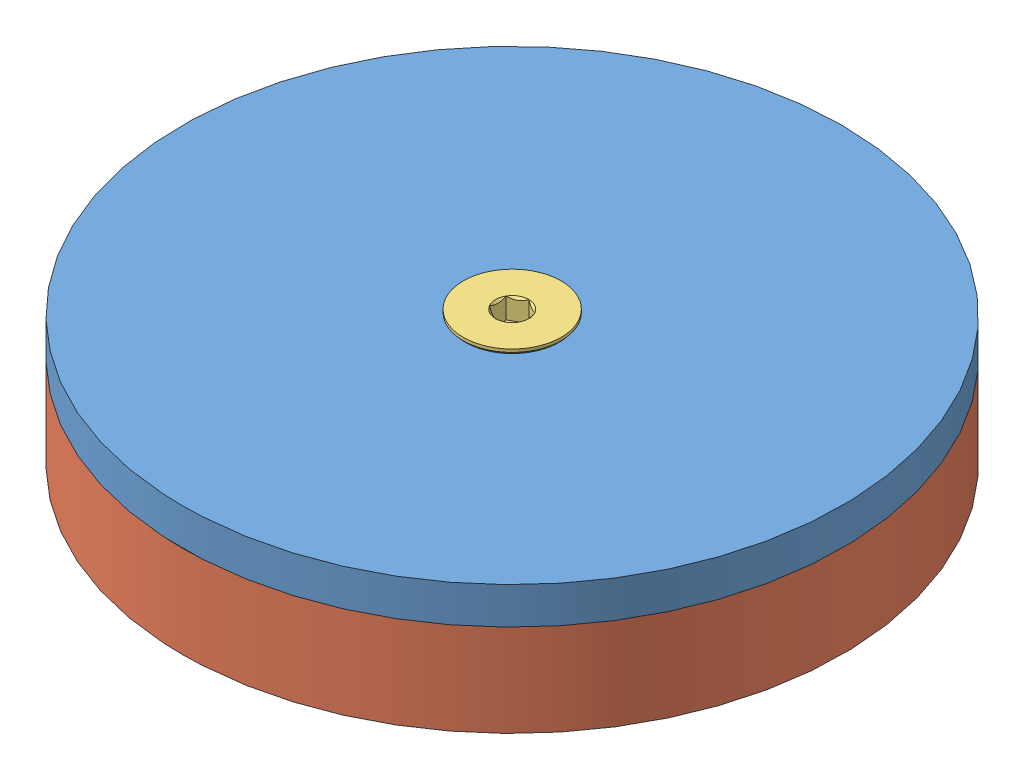
SolidWorks assembly ST_CAP_ASSEM, configuration Default. Lengths in mm.
Overall size (106.06 26.39 106.06).
3 component instances, 3 part files, 3 mates.
Components (placement in the parent):
- ST_Cap-1: ST_Cap [Default] at (-35.3765 13.1867 -3.2334) size (106.06 25.4 106.06)
- ST_Bottom-1: ST_Bottom [Default] at (-35.3765 20.809 -3.2334) size (90.93 12.7 90.93)
- 91263A556_ZINC-PLATED ALLOY STEEL FLAT-HEAD CAP SCREW-1: 91263A556_ZINC-PLATED ALLOY STEEL FLAT-HEAD CAP SCREW [91263A556] at (-35.3765 39.3463 -3.2334) x (1 0 0) z (0 1 0) size (13.49 13.49 16.52)
Mates (geometry in assembly coordinates):
- Concentric1: concentric: cylinder of ST_Cap-1 through (-35.3765 38.5867 -3.2334) axis (0 1 0) radius 3.2639; cylinder of ST_Bottom-1 through (-35.3765 20.809 -3.2334) axis (0 1 0) radius 3.302
- Coincident2: coincident: cone of ST_Cap-1 through (-35.3765 38.5867 -3.2334) axis (0 -1 0); cone of 91263A556_ZINC-PLATED ALLOY STEEL FLAT-HEAD CAP SCREW-1 through (-35.3765 35.2569 -3.2334) axis (0 -1 0)
- Coincident3: coincident: plane of ST_Cap-1 through (-35.3765 33.509 -3.2334) normal (0 -1 0); plane of ST_Bottom-1 through (-35.3765 33.509 -3.2334) normal (0 1 0)
